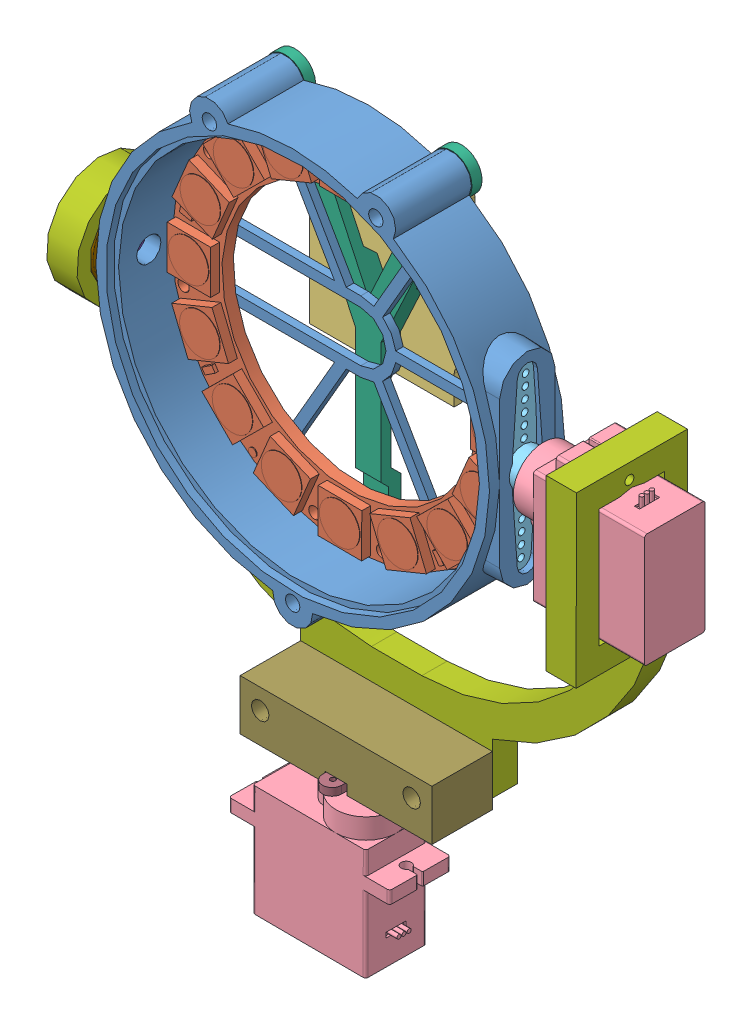
SolidWorks assembly assembly, configuration Default. Lengths in mm.
Overall size (114 139.39 25.13).
23 component instances, 13 part files, 28 mates.
Components (placement in the parent):
- ring-shell-1: ring-shell [Default] at (19.0926 43.4847 53.1336) size (78 82.25 15)
- NeoPixelRing16-d7-1: NeoPixelRing16-d7 [Default] at (19.0905 43.5003 55.614) x (-0.980853 -0.194751 0) z (0 0 1) size (70.4 70.4 4.08)
- ESP-wrover-B_board-1: ESP-wrover-B_board [Default] at (19.0905 54.7434 49.2336) x (-1 0 0) z (0 0 -1) size (31.2 39 3.1)
- servo-1: servo [Varsayılan] at (87.2926 38.2347 60.6442) x (0 0.002021 0.999998) z (0 -0.999998 0.002021) size (12 30 32)
- servo horn 2 v1-1: servo horn 2 v1 [Default] at (57.2926 43.4847 60.6336) x (0 -0.029252 -0.999572) z (0 0.999572 -0.029252) size (7.2 3.7 35.2)
- esp-case-2: esp-case [Default] at (19.0905 43.5003 53.1336) x (-1 0 0) z (0 0 -1) size (41.06 82.45 4)
- arm-1: arm [Default] at (25.7926 32.4615 49.1558) x (1 0 0) z (0 0.002021 0.999998) size (105 77.5 22)
- bearing 625-1: bearing 625 [Default] at (-25.7074 43.4837 60.1336) size (5 16 16)
  - SKF 625.STEP-1: SKF 625.STEP [Default] at origin size (5 16 16)
    - SKF 625 Inner Race^SKF 625.STEP-1: SKF 625 Inner Race^SKF 625.STEP [Default] at origin size (5 8.4 8.4)
    - SKF 625 Outer Race^SKF 625.STEP-1: SKF 625 Outer Race^SKF 625.STEP [Default] at origin size (5 16 16)
    - SKF 625 Ball^SKF 625.STEP-1: SKF 625 Ball^SKF 625.STEP [Default] at origin size (2.38 2.38 2.38)
    - SKF 625 Ball^SKF 625.STEP-2: SKF 625 Ball^SKF 625.STEP [Default] x (1 0 0) z (0 0.707107 0.707107) size (2.38 2.38 2.38)
    - SKF 625 Ball^SKF 625.STEP-3: SKF 625 Ball^SKF 625.STEP [Default] x (1 0 0) z (0 1 0) size (2.38 2.38 2.38)
    - SKF 625 Ball^SKF 625.STEP-4: SKF 625 Ball^SKF 625.STEP [Default] x (1 0 0) z (0 0.707107 -0.707107) size (2.38 2.38 2.38)
    - SKF 625 Ball^SKF 625.STEP-5: SKF 625 Ball^SKF 625.STEP [Default] x (1 0 0) z (0 0 -1) size (2.38 2.38 2.38)
    - SKF 625 Ball^SKF 625.STEP-6: SKF 625 Ball^SKF 625.STEP [Default] x (1 0 0) z (0 -0.707107 -0.707107) size (2.38 2.38 2.38)
    - SKF 625 Ball^SKF 625.STEP-7: SKF 625 Ball^SKF 625.STEP [Default] x (1 0 0) z (0 -1 0) size (2.38 2.38 2.38)
    - SKF 625 Ball^SKF 625.STEP-8: SKF 625 Ball^SKF 625.STEP [Default] x (1 0 0) z (0 -0.707107 0.707107) size (2.38 2.38 2.38)
    - SKF 625 Cage^SKF 625.STEP-1: SKF 625 Cage^SKF 625.STEP [Default] at (2.5 0 0) x (0 0 -1) z (1 0 0) size (12.17 12.17 2.88)
- sg90-adapter-1: sg90-adapter [Default] at (25.7926 -20.0283 54.2619) x (1 0 0) z (0 0.002021 0.999998) size (38 10 12)
- SG90 horn-cross-1: SG90 horn-cross [Varsayılan] at (25.7926 -24.5161 60.271) x (1 0 0) z (0 0.002021 0.999998) size (34.3 4 16.6)
- servo-2: servo [Varsayılan] at (20.5427 -54.5161 60.3072) x (-0.004653 0.002021 0.999987) z (-0.999989 -0.000009 -0.004653) size (12 30 32)
Mates (geometry in assembly coordinates):
- Coincident1: coincident anti-aligned: plane of ring-shell-1 through (19.0926 43.4847 54.6336) normal (0 0 1); plane of NeoPixelRing16-d7-1 through (19.0882 43.0207 54.6336) normal (0 0 -1)
- Concentric1: concentric anti-aligned: cylinder of ring-shell-1 through (19.0926 43.4847 68.1336) axis (0 0 -1) radius 36; circle of NeoPixelRing16-d7-1
- Coincident2: coincident anti-aligned: plane of ring-shell-1 through (56.0926 27.4847 60.6336) normal (1 0 0); plane of servo horn 2 v1-1 through (56.0926 36.4877 60.8383) normal (-1 0 0)
- Coincident4: coincident anti-aligned: plane of ring-shell-1 through (19.0926 43.4847 53.1336) normal (0 0 -1); plane of esp-case-1 through (19.3316 43.1534 53.1336) normal (0 0 1)
- Coincident5: coincident anti-aligned: plane of ring-shell-1 through (19.0926 43.4847 53.1336) normal (0 0 -1); plane of esp-case-2 through (19.0905 43.5003 53.1336) normal (0 0 1)
- Coincident6: coincident aligned: circle of ESP-wrover-B_board-1; circle of esp-case-2
- Coincident7: coincident aligned: circle of ESP-wrover-B_board-1; circle of esp-case-2
- Concentric5: concentric aligned: circle of servo-1; cylinder of servo horn 2 v1-1 through (57.2926 43.4847 60.6336) axis (-1 0 0) radius 2.5
- Concentric6: concentric aligned: circle of ring-shell-1; circle of servo horn 2 v1-1
- Parallel1: parallel anti-aligned: plane of ring-shell-1 through (66.0926 59.6264 62.6286) normal (0 -0.07084 -0.997488); plane of servo horn 2 v1-1 through (57.2926 47.1563 63.0272) normal (0 0.07084 0.997488)
- Concentric7: concentric anti-aligned: circle of ring-shell-1; circle of esp-case-2
- Concentric8: concentric anti-aligned: circle of ring-shell-1; circle of esp-case-2
- Coincident10: coincident anti-aligned: plane of servo-1 through (72.2926 22.7459 66.1755) normal (1 0 0); plane of arm-1 through (72.2926 32.4615 49.1558) normal (-1 0 0)
- Coincident11: coincident anti-aligned: plane of servo-1 through (57.2926 43.4847 60.6336) normal (-1 0 0); plane of servo horn 2 v1-1 through (57.2926 43.4847 60.6336) normal (1 0 0)
- Concentric9: concentric aligned: cylinder of arm-1 through (-26.7074 43.4837 60.1336) axis (1 0 0) radius 8.35; cylinder of bearing 625-1/SKF 625.STEP-1/SKF 625 Outer Race^SKF 625.STEP-1 through (-21.0074 43.4837 60.1336) axis (1 0 0) radius 8
- Coincident12: coincident anti-aligned: plane of arm-1 through (-25.7074 43.4837 60.1336) normal (1 0 0); plane of bearing 625-1/SKF 625.STEP-1/SKF 625 Outer Race^SKF 625.STEP-1 through (-25.7074 51.1837 60.1336) normal (-1 0 0)
- Coincident13: coincident anti-aligned: plane of servo-1 through (86.2926 48.9968 66.6225) normal (0 0.002021 0.999998); plane of arm-1 through (78.2926 32.4969 66.6558) normal (0 -0.002021 -0.999998)
- Coincident14: coincident anti-aligned: plane of servo-1 through (86.2926 49.4736 55.1215) normal (0 0.999998 -0.002021); plane of arm-1 through (78.2926 49.4615 49.1215) normal (0 -0.999998 0.002021)
- Coincident15: coincident anti-aligned: circle of arm-1; circle of sg90-adapter-1
- Coincident16: coincident anti-aligned: plane of arm-1 through (25.7926 32.4716 54.1558) normal (0 0.002021 0.999998); plane of sg90-adapter-1 through (25.7926 -20.0283 54.2619) normal (0 -0.002021 -0.999998)
- Concentric10: concentric aligned: circle of arm-1; circle of sg90-adapter-1
- Concentric12: concentric aligned: circle of sg90-adapter-1; circle of servo horn 2 v1-2
- Parallel2: parallel aligned: plane of sg90-adapter-1 through (25.7926 -20.004 66.2619) normal (0 0.002021 0.999998); plane of servo horn 2 v1-2 through (28.383 -24.4815 56.5745) normal (0 -0.088913 0.996039)
- Concentric13: concentric anti-aligned: circle of sg90-adapter-1; circle of SG90 horn-cross-1
- Parallel4: parallel aligned: plane of sg90-adapter-1 through (6.7926 -15.004 66.2518) normal (-1 0 0); plane of SG90 horn-cross-1 through (23.8926 -23.0161 60.268) normal (-1 0 0)
- Coincident25: coincident anti-aligned: plane of sg90-adapter-1 through (8.8426 -23.0161 60.268) normal (0 -0.999998 0.002021); plane of SG90 horn-cross-1 through (25.7926 -23.0161 60.268) normal (0 0.999998 -0.002021)
- Concentric14: concentric anti-aligned: circle of SG90 horn-cross-1; circle of servo-2
- Coincident26: coincident anti-aligned: plane of SG90 horn-cross-1 through (25.7926 -24.5161 60.271) normal (0 -0.999998 0.002021); plane of servo-2 through (25.7926 -24.5161 60.271) normal (0 0.999998 -0.002021)
